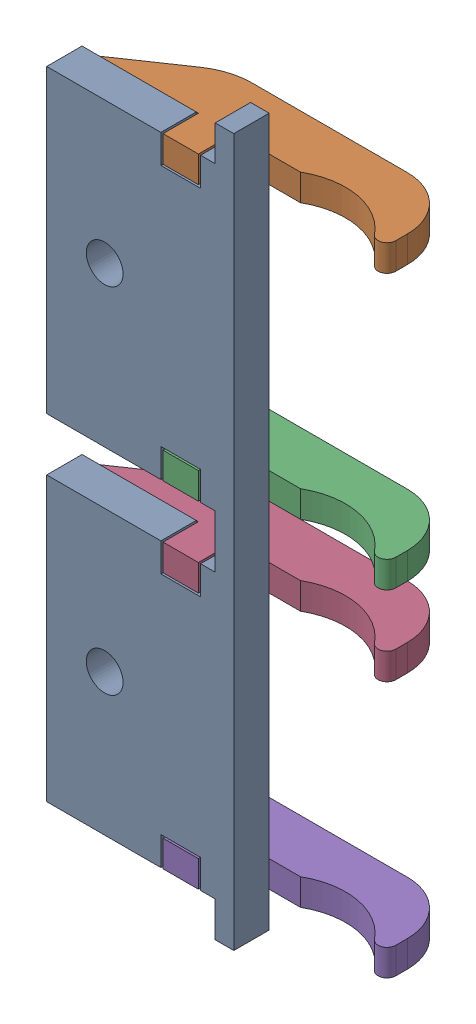
SolidWorks assembly AC-A0204-AA-Chassis Side Mount Assembly1, configuration Default. Lengths in mm.
Overall size (58.42 127 15.88).
9 component instances, 2 part files, 18 mates.
Components (placement in the parent):
- AC-30039-AA-Side Chassis Mounts1-1: AC-30039-AA-Side Chassis Mounts1 [Default] at (42.9845 -120.0464 -13.4601) size (33.59 127 6.35)
- AC-30041-AA-Side Mount Gusset1-1: AC-30041-AA-Side Mount Gusset1 [Default] at (50.035 0.6036 -13.4601) x (1 0 0) z (0 0 -1) size (55.25 4.76 15.88)
- AC-30041-AA-Side Mount Gusset1-6: AC-30041-AA-Side Mount Gusset1 [Default] at (50.035 -48.6089 -13.4601) x (1 0 0) z (0 0 -1) size (55.25 4.76 15.88)
- AC-30041-AA-Side Mount Gusset1-7: AC-30041-AA-Side Mount Gusset1 [Default] at (50.035 -62.8964 -13.4601) x (1 0 0) z (0 0 -1) size (55.25 4.76 15.88)
- AC-30041-AA-Side Mount Gusset1-8: AC-30041-AA-Side Mount Gusset1 [Default] at (50.035 -108.9339 -13.4601) x (1 0 0) z (0 0 -1) size (55.25 4.76 15.88)
- AC-30041-AA-Side Mount Gusset1-9: AC-30041-AA-Side Mount Gusset1 [Default] at (50.035 -113.6964 -7.1101) size (55.25 4.76 15.88) (suppressed, hidden)
- AC-30041-AA-Side Mount Gusset1-10: AC-30041-AA-Side Mount Gusset1 [Default] at (50.035 -67.6589 -7.1101) size (55.25 4.76 15.88) (suppressed, hidden)
- AC-30041-AA-Side Mount Gusset1-11: AC-30041-AA-Side Mount Gusset1 [Default] at (50.035 -53.3714 -7.1101) size (55.25 4.76 15.88) (suppressed, hidden)
- AC-30041-AA-Side Mount Gusset1-12: AC-30041-AA-Side Mount Gusset1 [Default] at (50.035 -4.1589 -7.1101) size (55.25 4.76 15.88) (suppressed, hidden)
Mates (geometry in assembly coordinates):
- Coincident12: coincident aligned: plane of AC-30039-AA-Side Chassis Mounts-1 through (42.9845 0.6036 -13.4601) normal (0 1 0); plane of AC-30041-AA-Side Mount Gusset-1 through (50.035 0.6036 -13.4601) normal (0 1 0)
- Coincident13: coincident anti-aligned: plane of AC-30039-AA-Side Chassis Mounts-1 through (42.9845 -120.0464 -13.4601) normal (0 0 -1); plane of AC-30041-AA-Side Mount Gusset-1 through (50.035 -4.1589 -13.4601) normal (0 0 1)
- Width3: width aligned: plane of AC-30041-AA-Side Mount Gusset-1 through (77.2745 -4.1589 -13.4601) normal (1 0 0); plane of AC-30041-AA-Side Mount Gusset-1 through (70.9245 -4.1589 -13.4601) normal (-1 0 0); plane of AC-30039-AA-Side Chassis Mounts-1 through (70.5435 -120.0464 -13.4601) normal (1 0 0); plane of AC-30039-AA-Side Chassis Mounts-1 through (77.6555 -120.0464 -13.4601) normal (-1 0 0)
- Coincident15: coincident aligned: plane of AC-30039-AA-Side Chassis Mounts-1 through (42.9845 -53.3714 -13.4601) normal (0 -1 0); plane of AC-30041-AA-Side Mount Gusset-6 through (50.035 -53.3714 -13.4601) normal (0 -1 0)
- Width4: width aligned: plane of AC-30041-AA-Side Mount Gusset-6 through (77.2745 -53.3714 -13.4601) normal (1 0 0); plane of AC-30041-AA-Side Mount Gusset-6 through (70.9245 -53.3714 -13.4601) normal (-1 0 0); plane of AC-30039-AA-Side Chassis Mounts-1 through (70.5435 -120.0464 -13.4601) normal (1 0 0); plane of AC-30039-AA-Side Chassis Mounts-1 through (77.6555 -120.0464 -13.4601) normal (-1 0 0)
- Coincident17: coincident anti-aligned: plane of AC-30039-AA-Side Chassis Mounts-1 through (42.9845 -120.0464 -13.4601) normal (0 0 -1); plane of AC-30041-AA-Side Mount Gusset-6 through (50.035 -53.3714 -13.4601) normal (0 0 1)
- Coincident18: coincident aligned: plane of AC-30039-AA-Side Chassis Mounts-1 through (42.9845 -62.8964 -13.4601) normal (0 1 0); plane of AC-30041-AA-Side Mount Gusset-7 through (50.035 -62.8964 -13.4601) normal (0 1 0)
- Coincident19: coincident anti-aligned: plane of AC-30039-AA-Side Chassis Mounts-1 through (42.9845 -120.0464 -13.4601) normal (0 0 -1); plane of AC-30041-AA-Side Mount Gusset-7 through (50.035 -67.6589 -13.4601) normal (0 0 1)
- Width5: width aligned: plane of AC-30041-AA-Side Mount Gusset-7 through (77.2745 -67.6589 -13.4601) normal (1 0 0); plane of AC-30041-AA-Side Mount Gusset-7 through (70.9245 -67.6589 -13.4601) normal (-1 0 0); plane of AC-30039-AA-Side Chassis Mounts-1 through (70.5435 -120.0464 -13.4601) normal (1 0 0); plane of AC-30039-AA-Side Chassis Mounts-1 through (77.6555 -120.0464 -13.4601) normal (-1 0 0)
- Coincident21: coincident aligned: plane of AC-30039-AA-Side Chassis Mounts-1 through (42.9845 -113.6964 -13.4601) normal (0 -1 0); plane of AC-30041-AA-Side Mount Gusset-8 through (50.035 -113.6964 -13.4601) normal (0 -1 0)
- Width6: width anti-aligned: plane of AC-30039-AA-Side Chassis Mounts-1 through (77.6555 -120.0464 -13.4601) normal (-1 0 0); plane of AC-30039-AA-Side Chassis Mounts-1 through (70.5435 -120.0464 -13.4601) normal (1 0 0); plane of AC-30041-AA-Side Mount Gusset-8 through (77.2745 -113.6964 -13.4601) normal (1 0 0); plane of AC-30041-AA-Side Mount Gusset-8 through (70.9245 -113.6964 -13.4601) normal (-1 0 0)
- Coincident23: coincident anti-aligned: plane of AC-30039-AA-Side Chassis Mounts-1 through (42.9845 -120.0464 -13.4601) normal (0 0 -1); plane of AC-30041-AA-Side Mount Gusset-8 through (50.035 -113.6964 -13.4601) normal (0 0 1)
- Coincident24: coincident aligned: plane of AC-30039-AA-Side Chassis Mounts-1 through (42.9845 -113.6964 -13.4601) normal (0 -1 0); plane of AC-30041-AA-Side Mount Gusset-9 through (50.035 -113.6964 -7.1101) normal (0 -1 0)
- Width1: width aligned: plane of AC-30041-AA-Side Mount Gusset-9 through (77.2745 -108.9339 -7.1101) normal (1 0 0); plane of AC-30039-AA-Side Chassis Mounts-1 through (70.9245 -108.9339 -7.1101) normal (-1 0 0); plane of AC-30041-AA-Side Mount Gusset-9 through (70.5435 -120.0464 -13.4601) normal (1 0 0); plane of AC-30039-AA-Side Chassis Mounts-1 through (77.6555 -120.0464 -13.4601) normal (-1 0 0)
- Coincident26: coincident anti-aligned: plane of AC-30039-AA-Side Chassis Mounts-1 through (42.9845 -120.0464 -7.1101) normal (0 0 1); plane of AC-30041-AA-Side Mount Gusset-9 through (50.035 -108.9339 -7.1101) normal (0 0 -1)
- Coincident27: coincident aligned: plane of AC-30039-AA-Side Chassis Mounts-1 through (42.9845 -53.3714 -13.4601) normal (0 -1 0); plane of AC-30041-AA-Side Mount Gusset-11 through (50.035 -53.3714 -7.1101) normal (0 -1 0)
- Coincident28: coincident anti-aligned: plane of AC-30039-AA-Side Chassis Mounts-1 through (42.9845 -120.0464 -7.1101) normal (0 0 1); plane of AC-30041-AA-Side Mount Gusset-11 through (50.035 -48.6089 -7.1101) normal (0 0 -1)
- Width2: width aligned: plane of AC-30039-AA-Side Chassis Mounts-1 through (70.5435 -120.0464 -13.4601) normal (1 0 0); plane of AC-30041-AA-Side Mount Gusset-11 through (77.6555 -120.0464 -13.4601) normal (-1 0 0); plane of AC-30039-AA-Side Chassis Mounts-1 through (77.2745 -48.6089 -7.1101) normal (1 0 0); plane of AC-30041-AA-Side Mount Gusset-11 through (70.9245 -48.6089 -7.1101) normal (-1 0 0)
